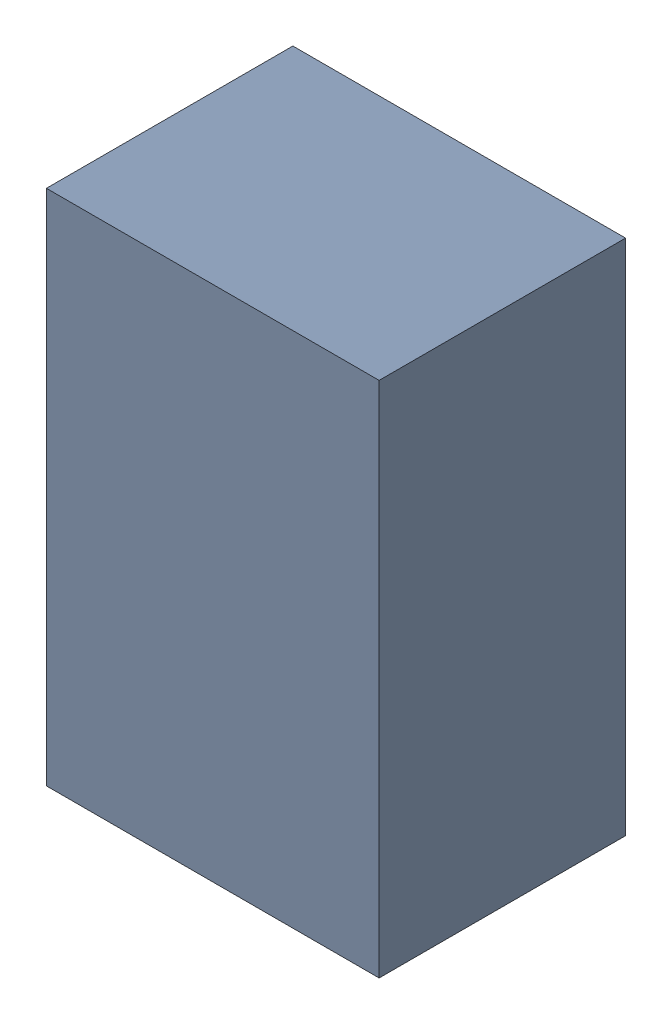
SolidWorks assembly U21, configuration ﾃﾞﾌｫﾙﾄ. Lengths in mm.
Overall size (1.35 2.1 1).
2 component instances, 1 part files, 0 mates.
Components (placement in the parent):
- 689262600-1: 689262600 [ﾃﾞﾌｫﾙﾄ] at (43.25 51.75 0) size (1.35 2.1 1)
  - Extruded_41-1: Extruded_41 [ﾃﾞﾌｫﾙﾄ] at origin size (1.35 2.1 1)
